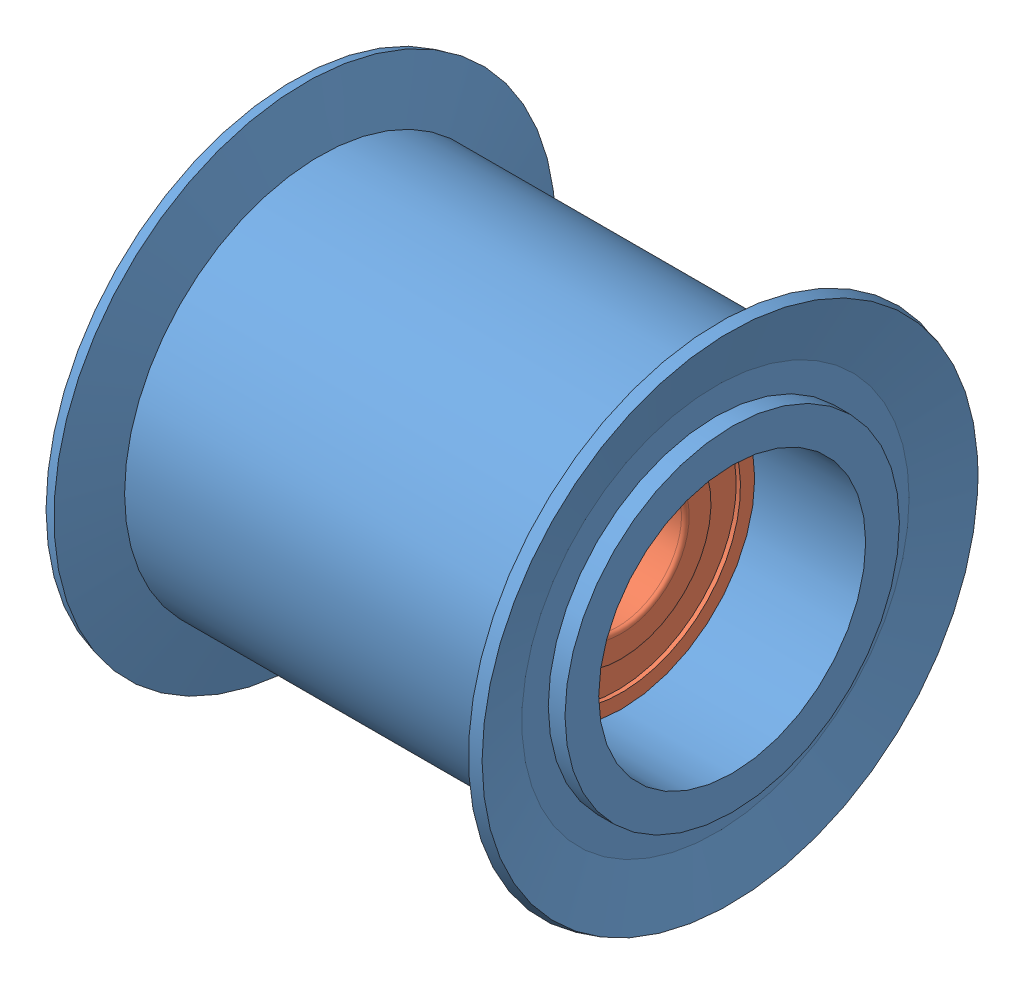
SolidWorks assembly AFDF22-35, configuration Default. Lengths in mm.
Overall size (17.17 19.57 19.57).
5 component instances, 4 part files, 6 mates.
Components (placement in the parent):
- AFDF22-35_bo2-1: AFDF22-35_bo2 [Default] at (-0.005 15.9206 -40.7266) size (17.17 19.57 19.57)
- bearing_6000_2-1: bearing_6000_2 [Default] at (-1.1407 15.9206 -40.7266) x (1 0 0) z (0 0.725871 -0.68783) size (4 11.3 11.3)
- RTWS26_2-1: RTWS26_2 [Default] at (3.4593 16.2491 -40.6916) x (1 0 0) z (0 -0.105995 0.994367) size (1.2 11.46 11.98)
- bearing_6000_2-2: bearing_6000_2 [Default] at (4.0593 15.9206 -40.7266) x (1 0 0) z (0 0.725871 -0.68783) size (4 11.3 11.3)
- AFDF22-35_d-1: AFDF22-35_d [Default] at origin
Mates (geometry in assembly coordinates):
- Concentric1: concentric aligned: cylinder of AFDF22-35_bo2-1 through (-4.7898 15.9206 -40.7266) axis (1 0 0) radius 5.6522; cylinder of bearing_6000_2-1 through (-1.1432 15.9206 -40.7266) axis (1 0 0) radius 2.5
- Coincident3: coincident anti-aligned: plane of bearing_6000_2-1 through (2.8593 12.7222 -44.1019) normal (1 0 0); plane of RTWS26_2-1 through (2.8593 11.9268 -43.4177) normal (-1 0 0)
- Coincident4: coincident anti-aligned: plane of AFDF22-35_bo2-1 through (4.0593 21.5727 -40.7266) normal (-1 0 0); plane of RTWS26_2-1 through (4.0593 11.9268 -43.4177) normal (1 0 0)
- Concentric3: concentric aligned: cylinder of bearing_6000_2-1 through (-1.1432 15.9206 -40.7266) axis (1 0 0) radius 2.5; cylinder of RTWS26_2-1 through (2.8593 15.9206 -40.7266) axis (1 0 0) radius 5
- Coincident5: coincident aligned: plane of RTWS26_2-1 through (4.0593 11.9268 -43.4177) normal (1 0 0); circle of bearing_6000_2-2
- Concentric4: concentric aligned: cylinder of bearing_6000_2-1 through (-1.1432 15.9206 -40.7266) axis (1 0 0) radius 2.5; cylinder of bearing_6000_2-2 through (4.0568 15.9206 -40.7266) axis (1 0 0) radius 2.5
